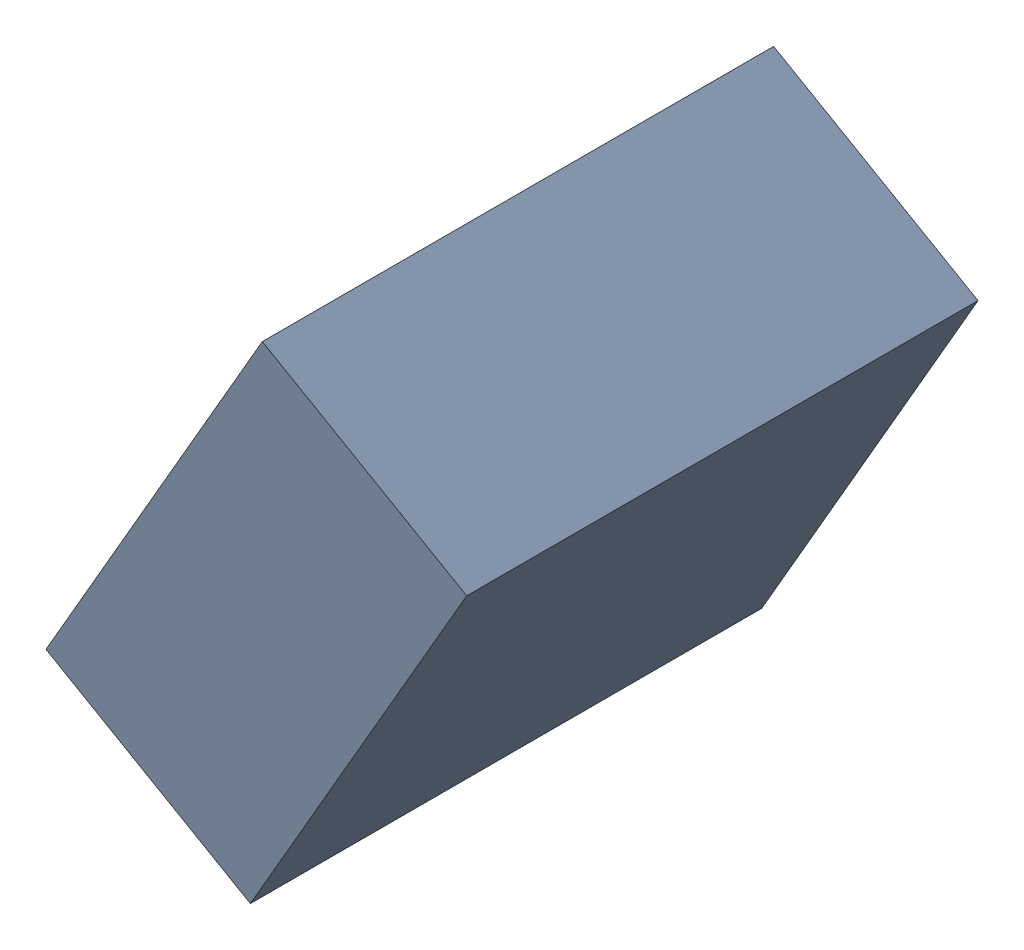
SolidWorks assembly C24_TDA3, configuration Standard. Lengths in mm.
Overall size (1.07 1.25 1.3).
2 component instances, 1 part files, 0 mates.
Components (placement in the parent):
- 885543328-1: 885543328 [Standard] at (37.7624 -23.6849 0) size (1.07 1.25 1.3)
  - Extruded_26-1: Extruded_26 [Standard] at origin size (1.07 1.25 1.3)
